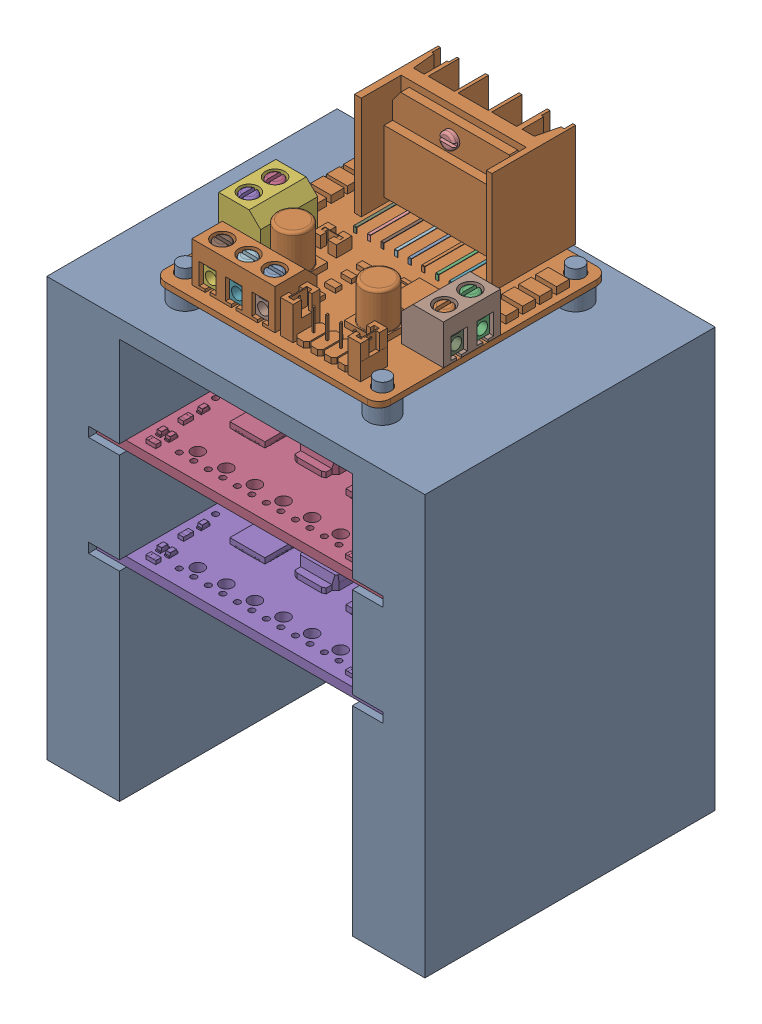
SolidWorks assembly ServerRackAssembly, configuration Default. Lengths in mm.
Overall size (66.17 95.43 50.8).
4 component instances, 3 part files, 12 mates.
Components (placement in the parent):
- ServerRack-1: ServerRack [Default] at origin size (66.17 78.97 50.8)
- L298N-1: L298N [Default] at (43.8588 59.9512 56.2762) x (-1 0 0) z (0 0 -1) size (39.39 19 41.67)
- dual-tb9051ftg-motor-driver-shield-1: dual-tb9051ftg-motor-driver-shield [Default] at (7.4295 52.5018 1.27) x (0 0 1) z (0 1 0) size (48.26 51.31 7.68)
- dual-tb9051ftg-motor-driver-shield-2: dual-tb9051ftg-motor-driver-shield [Default] at (7.4295 34.925 1.27) x (0 0 1) z (0 1 0) size (48.26 51.31 7.68)
Mates (geometry in assembly coordinates):
- Parallel1: parallel: plane of ServerRack-1 through (0 0 0) normal (0 0 -1); plane of L298N-1 through (15.3881 84.5427 5.3244) normal (0 0 -1)
- Width1: width: plane of L298N-1 through (52.7789 84.5427 7.3244) normal (1 0 0); plane of ServerRack-1 through (13.3881 84.5427 7.3244) normal (-1 0 0); plane of L298N-1 through (0 0 50.8) normal (-1 0 0); plane of ServerRack-1 through (66.167 0 50.8) normal (1 0 0)
- Width2: width: plane of L298N-1 through (15.3881 84.5427 5.3244) normal (0 0 -1); plane of ServerRack-1 through (15.3881 84.5427 45.4756) normal (0 0 1); plane of L298N-1 through (0 0 50.8) normal (0 0 1); plane of ServerRack-1 through (0 0 0) normal (0 0 -1)
- Parallel2: parallel aligned: plane of ServerRack-1 through (0 73.2536 50.8) normal (0 1 0); plane of dual-tb9051ftg-motor-driver-shield-1 through (7.4295 54.0766 1.27) normal (0 1 0)
- Parallel3: parallel aligned: plane of ServerRack-1 through (0 0 50.8) normal (0 0 1); plane of dual-tb9051ftg-motor-driver-shield-1 through (7.4295 54.0766 49.53) normal (0 0 1)
- Width3: width anti-aligned: plane of dual-tb9051ftg-motor-driver-shield-1 through (7.4295 54.0766 1.27) normal (-1 0 0); plane of ServerRack-1 through (58.7375 54.0766 49.53) normal (1 0 0); plane of dual-tb9051ftg-motor-driver-shield-1 through (7.3025 54.2036 50.8) normal (1 0 0); plane of ServerRack-1 through (58.8645 54.2036 50.8) normal (-1 0 0)
- Coincident4: coincident anti-aligned: plane of ServerRack-1 through (7.3025 52.5018 50.8) normal (0 1 0); plane of dual-tb9051ftg-motor-driver-shield-1 through (7.4295 52.5018 1.27) normal (0 -1 0)
- Width4: width aligned: plane of dual-tb9051ftg-motor-driver-shield-1 through (7.4295 54.0766 49.53) normal (0 0 1); plane of ServerRack-1 through (58.7375 54.0766 1.27) normal (0 0 -1); plane of dual-tb9051ftg-motor-driver-shield-1 through (0 0 50.8) normal (0 0 1); plane of ServerRack-1 through (0 0 0) normal (0 0 -1)
- Width5: width anti-aligned: plane of dual-tb9051ftg-motor-driver-shield-2 through (58.7375 36.4998 49.53) normal (1 0 0); plane of ServerRack-1 through (7.4295 36.4998 1.27) normal (-1 0 0); plane of dual-tb9051ftg-motor-driver-shield-2 through (58.8645 36.6268 50.8) normal (-1 0 0); plane of ServerRack-1 through (7.3025 36.6268 50.8) normal (1 0 0)
- Width6: width anti-aligned: plane of dual-tb9051ftg-motor-driver-shield-2 through (58.7375 36.4998 1.27) normal (0 0 -1); plane of ServerRack-1 through (7.4295 36.4998 49.53) normal (0 0 1); plane of dual-tb9051ftg-motor-driver-shield-2 through (0 0 50.8) normal (0 0 1); plane of ServerRack-1 through (0 0 0) normal (0 0 -1)
- Coincident5: coincident anti-aligned: plane of ServerRack-1 through (7.3025 34.925 50.8) normal (0 1 0); plane of dual-tb9051ftg-motor-driver-shield-2 through (7.4295 34.925 1.27) normal (0 -1 0)
- Coincident6: coincident anti-aligned: plane of ServerRack-1 through (15.6633 76.4286 42.2283) normal (0 1 0); plane of L298N-1 through (50.7789 76.4286 43.4756) normal (0 -1 0)
